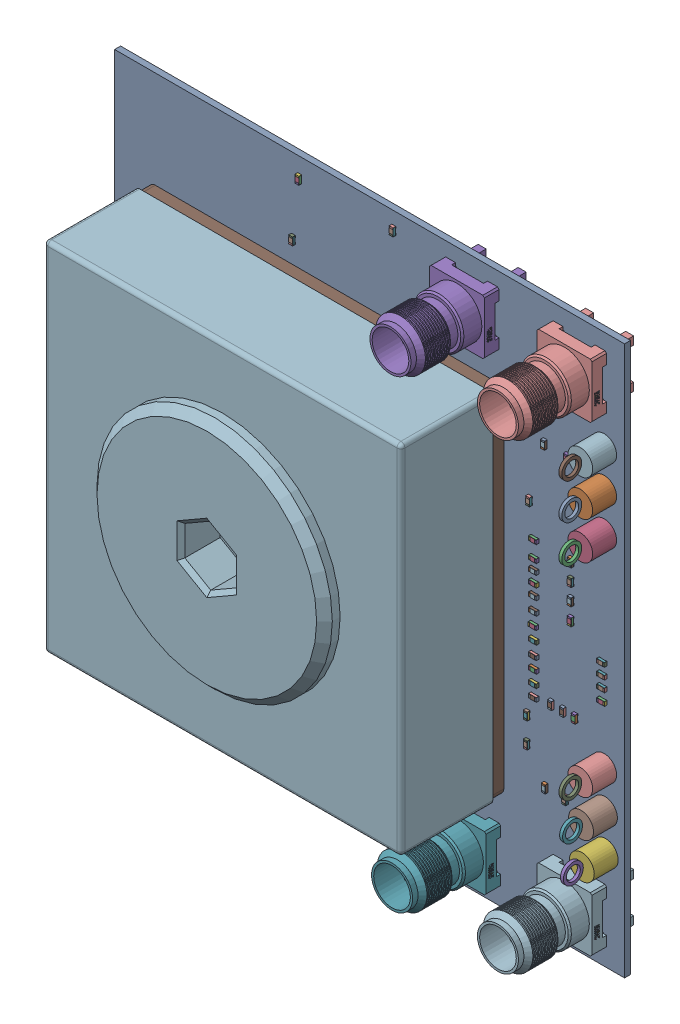
SolidWorks assembly ironwood_carrier_asm, configuration Default. Lengths in mm.
Overall size (65 70 24.83).
3 component instances, 3 part files, 6 mates.
Components (placement in the parent):
- SP24 Bringup Carrier-1: SP24 Bringup Carrier [Default] at origin size (65 70 19.87)
- Ironwood_socket_bottom-1: Ironwood_socket_bottom [Default] at (27.0474 35.0474 -9.4619) x (1 0 0) z (0 -1 0) size (45.5 7.5 45.5)
- Ironwood_socket_top-1: Ironwood_socket_top [Default] at (27.0474 35.0474 1.5951) x (1 0 0) z (0 -1 0) size (45.5 18.7 45.5)
Mates (geometry in assembly coordinates):
- Coincident1: coincident anti-aligned: plane of SP24 Bringup Carrier-1 through (50.8624 58.8624 -1.9619) normal (0 0 -1); plane of Ironwood_socket_bottom-1 through (27.0474 35.0474 -1.9619) normal (0 0 1)
- Distance1: distance = 1.16 mm aligned: plane of SP24 Bringup Carrier-1 through (3.1374 11.1374 -0.3719) normal (-1 0 0); plane of Ironwood_socket_bottom-1 through (4.2974 12.2974 -1.9619) normal (-1 0 0)
- Distance2: distance = 1.16 mm aligned: plane of SP24 Bringup Carrier-1 through (3.1374 11.1374 -0.3719) normal (0 -1 0); plane of Ironwood_socket_bottom-1 through (4.2974 12.2974 -1.9619) normal (0 -1 0)
- Concentric1: concentric aligned: cylinder of Ironwood_socket_bottom-1 through (27.0474 35.0474 -6.9619) axis (0 0 1) radius 15; cylinder of Ironwood_socket_top-1 through (27.0474 35.0474 -3.4049) axis (0 0 1) radius 15
- Coincident5: coincident anti-aligned: plane of SP24 Bringup Carrier-1 through (27 35 1.5951) normal (0 0 1); plane of Ironwood_socket_top-1 through (27.0474 35.0474 1.5951) normal (0 0 -1)
- Coincident6: coincident aligned: plane of Ironwood_socket_bottom-1 through (4.2974 12.2974 -1.9619) normal (-1 0 0); plane of Ironwood_socket_top-1 through (4.2974 12.2974 13.2951) normal (-1 0 0)
